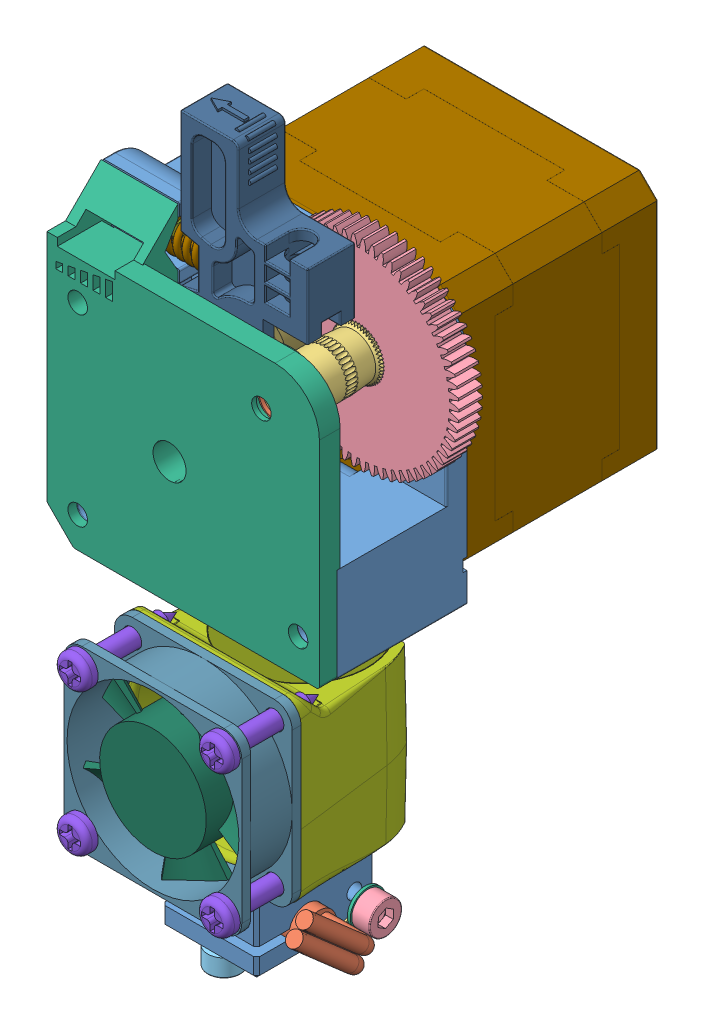
SolidWorks assembly E3D_Titan_with_V6, configuration Default. Lengths in mm.
Overall size (60.69 115.67 77.03).
34 component instances, 27 part files, 10 mates.
Components (placement in the parent):
- e3d titan-1: e3d titan [Default] at (0 20.7 0) x (-1 0 0) z (0 1 0) size (60.24 25.35 66.08)
  - E3D_Titan_Base-1: E3D_Titan_Base [Default] at origin size (46 23.41 49.98)
  - 9x5x3mm bearing-1: 9x5x3mm bearing [Default] at (-15.5 4 15.5) x (0.988909 0 0.148526) z (0 -1 0) size (9 9 3)
  - hobbed wheel-1: hobbed wheel [Default] at (-15.5 1.6 15.5) x (-0.707107 0 0.707107) z (0 1 0) size (8.6 8.58 20.6)
  - filament gear-1: filament gear [Default] at (-15.5 8.55 15.5) x (-0.707107 0 -0.707107) z (0 -1 0) size (34 34 4)
  - motor gear-1: motor gear [Default] at (0 8.55 0) x (0.707107 0 0.707107) z (0 -1 0) size (11.99 11.99 9)
  - cover-1: cover [Default] at (0 24.9 0) x (1 0 0) z (0 0 -1) size (46 9.13 49.98)
  - 9x5x3mm bearing-2: 9x5x3mm bearing [Default] at (-15.5 22.8 15.5) x (0.922034 0 0.38711) z (0 -1 0) size (9 9 3)
  - m3x8-1: m3x8 [Default] at (17.599 13.6 23.3) x (0 0.404015 0.914752) z (0 0.914752 -0.404015) size (5.69 9.65 5.69)
  - M3 nut-1: M3 nut [Default] at (15.913 13.6 23.3) x (0 1 0) z (0 0 1) size (6.19 2.71 6.57)
  - idler spring-1: idler spring [Default] at (13.5 13.6 23.3) x (0 -0.157848 0.987463) z (-1 0 0) size (6.43 6.45 12.02)
  - tensioner-1: tensioner [Default] at (0 13.6 0) x (0 -1 0) z (0 0 1) size (8.2 21.54 50.88)
  - idler bearing pin-1: idler bearing pin [Default] at (-5.5 9.6 15.5) x (0.997492 0 0.070785) z (0 1 0) size (3.04 3.15 9)
  - idler bearing-1: idler bearing [Default] at (-5.5 13.6 15.5) x (1 0 0) z (0 1 0) size (10 10 4)
  - guide tube-1: guide tube [Default] at (-10.9 13.6 -7.9) x (-1 0 0) z (0 0 1) size (10.9 16.1 22.25)
- E3D All Metal Hotend V6 assy-1: E3D All Metal Hotend V6 assy [Default] at (10.9 -30 13.6) x (0 0 -1) z (0 -1 0) size (38.16 34.25 62.3) (flexible)
  - Fan-DC-KDE0503PFB3-Promoco-1: Fan-DC-KDE0503PFB3-Promoco [Default] at (-15 0 -15) x (0 0 -1) z (-1 0 0) size (30 30 10)
    - Fan-House-30x30x10-Promoco(Fan-House-KDE0503PFB3-Promoco)-1: Fan-House-30x30x10-Promoco(Fan-House-KDE0503PFB3-Promoco) [Default] at origin size (30 30 10)
    - Fan-30x30x10-Promoco(Fan-KDE0503PFB3-Promoco)-1: Fan-30x30x10-Promoco(Fan-KDE0503PFB3-Promoco) [Default] x (0 0 -1) z (-0.999131 0.04169 0) size (8.5 27.91 28)
  - E3D v6 HotEnd - Heatsink-1: E3D v6 HotEnd - Heatsink [Default] at origin size (22.3 22.3 42.7)
  - E3D v6 HotEnd - Heatbreak-1: E3D v6 HotEnd - Heatbreak [Default] at (0 0 7.1) x (0.951461 0.30777 0) z (0 0 1) size (7 7 21.9)
  - E3D v6 HotEnd - Nozzle(ÃÞÌ«ÙÄ)-1: E3D v6 HotEnd - Nozzle(ÃÞÌ«ÙÄ) [Default] at (0 0 17.6) x (0.686854 0.726796 0) z (0 0 1) size (8.08 7 12.5)
  - E3D v6 HotEnd - Heat Block-1: E3D v6 HotEnd - Heat Block [Default] at (-15.5 8 13.6) x (1 0 0) z (0 1 0) size (20 11.5 16)
  - Ceramic Cartridge Heater-1: Ceramic Cartridge Heater [Default] at (-7 10 9.6) x (0.658614 0 -0.752481) z (0 1 0) size (6 18 29.25)
  - Thermistor-1: Thermistor [Default] at (2.5 3.65 11.6) x (0.939693 0 -0.34202) z (0 -1 0) size (4.52 1.5 4.65)
  - HEXAGON SOCKET HEAD CAP SCREWS(SCB3-4)-1: HEXAGON SOCKET HEAD CAP SCREWS(SCB3-4) [Default] at (2.5 8.8 11.6) x (0.999538 0 0.030402) z (0 1 0) size (5.5 5.5 7)
  - HEXAGON SOCKET HEAD CAP SCREWS(SCB3-10)-1: HEXAGON SOCKET HEAD CAP SCREWS(SCB3-10) [Default] at (-13 0 13.6) size (5.5 5.5 13)
  - Flat Washers(PWF3)-1: Flat Washers(PWF3) [Default] at (2.5 8.8 11.6) x (1 0 0) z (0 1 0) size (6 6 0.5)
  - E3D-v6 Fan Duct-1: E3D-v6 Fan Duct [Default] x (1 0 0) z (0 1 0) size (22.31 30.18 30)
  - Self Tapping Screws - Pan Head(CSPTRSA-SUS-TP3-16)-1: Self Tapping Screws - Pan Head(CSPTRSA-SUS-TP3-16) [Default] at (-25 12 -3) size (18.01 5.5 5.5)
  - Self Tapping Screws - Pan Head(CSPTRSA-SUS-TP3-16)-2: Self Tapping Screws - Pan Head(CSPTRSA-SUS-TP3-16) [Default] at (-25 -12 -27) size (18.01 5.5 5.5)
  - Self Tapping Screws - Pan Head(CSPTRSA-SUS-TP3-16)-3: Self Tapping Screws - Pan Head(CSPTRSA-SUS-TP3-16) [Default] at (-25 12 -27) size (18.01 5.5 5.5)
  - Self Tapping Screws - Pan Head(CSPTRSA-SUS-TP3-16)-4: Self Tapping Screws - Pan Head(CSPTRSA-SUS-TP3-16) [Default] at (-25 -12 -3) size (18.01 5.5 5.5)
- Nema17-42BYGHW811-1: Nema17-42BYGHW811 [Default] at (0 20.7 -36.4162) size (42.3 42.3 56)
Mates (geometry in assembly coordinates):
- Coincident1: coincident anti-aligned: plane of e3d titan-1/E3D_Titan_Base-1 through (2.3 22 0) normal (0 0 -1); plane of assembly through (0 0 0) normal (0 0 1)
- Coincident2: coincident anti-aligned: plane of e3d titan-1/E3D_Titan_Base-1; plane of assembly through (0 0 0) normal (1 0 0)
- Coincident3: coincident anti-aligned: plane of e3d titan-1/E3D_Titan_Base-1 through (-20.7 0 0) normal (0 -1 0); plane of assembly through (0 0 0) normal (0 1 0)
- Concentric1: concentric anti-aligned: cylinder of E3D All Metal Hotend V6 assy-1/E3D v6 HotEnd - Heatsink-1 through (10.9 -30 13.6) axis (0 -1 0) radius 6; cylinder of e3d titan-1/E3D_Titan_Base-1 through (10.9 3.15 13.6) axis (0 1 0) radius 6.3
- Coincident4: coincident anti-aligned: plane of e3d titan-1/E3D_Titan_Base-1 through (10.9 9 16.4493) normal (0 1 0); plane of E3D All Metal Hotend V6 assy-1/E3D v6 HotEnd - Heatsink-1 through (18.9 9 13.6) normal (0 -1 0)
- Parallel1: parallel anti-aligned: plane of E3D All Metal Hotend V6 assy-1/Fan-DC-KDE0503PFB3-Promoco-1/Fan-House-30x30x10-Promoco(Fan-House-KDE0503PFB3-Promoco)-1 through (10.9 -15 38.6) normal (0 0 1); plane of e3d titan-1/E3D_Titan_Base-1 through (2.3 22 0) normal (0 0 -1)
- Parallel2: parallel anti-aligned: plane of E3D All Metal Hotend V6 assy-1/E3D v6 HotEnd - Heat Block-1 through (2.9 -32.1 29.1) normal (0 0 1); plane of e3d titan-1/E3D_Titan_Base-1 through (2.3 22 0) normal (0 0 -1)
- Concentric3: concentric anti-aligned: cylinder of Nema17-42BYGHW811-1 through (-15.5 36.2 -2.4162) axis (0 0 1) radius 1.25; cylinder of e3d titan-1/E3D_Titan_Base-1 through (-15.5 36.2 3.5) axis (0 0 -1) radius 1.825
- Parallel3: parallel anti-aligned: plane of e3d titan-1/E3D_Titan_Base-1 through (2.3 22 0) normal (0 0 -1); plane of Nema17-42BYGHW811-1 through (21.15 41.85 -2.4162) normal (0 0 1)
- Parallel4: parallel aligned: plane of e3d titan-1/E3D_Titan_Base-1 through (25.3 44 0) normal (0 1 0); plane of Nema17-42BYGHW811-1 through (-21.15 41.85 -2.4162) normal (0 1 0)
